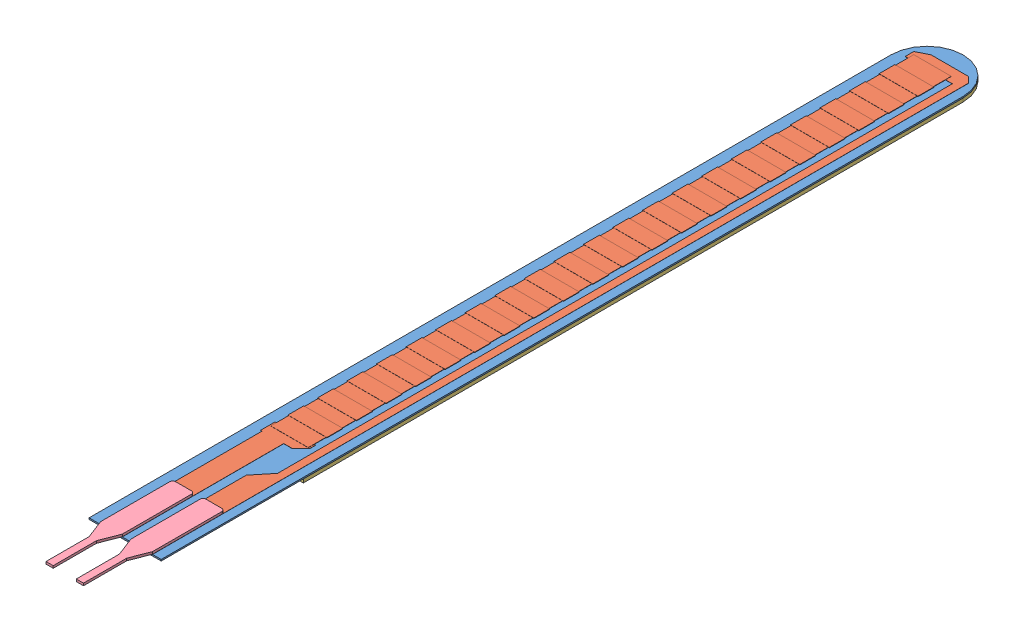
SolidWorks assembly FlexSensor, configuration Default. Lengths in mm.
Overall size (6.35 0.65 79.26).
5 component instances, 4 part files, 11 mates.
Components (placement in the parent):
- PlasticFilm-1: PlasticFilm [Default] at (-52.7883 12.8986 54.2802) size (6.35 0.13 73.81)
- Flex_Sensor_Circuit-1: Flex_Sensor_Circuit [Default] at origin size (4.83 0.04 72.39)
- Plastic_Stiffner-1: Plastic_Stiffner [Default] at (-52.7883 12.8986 54.2802) x (-1 0 0) z (0 -1 0) size (6.35 61.29 0.3)
- GoldProngTerminal-1: GoldProngTerminal [Default] at (0 13.0383 0) x (1 0 0) z (0 1 0) size (1.9 11.8 0.2)
- GoldProngTerminal-2: GoldProngTerminal [Default] at (-2.667 13.0383 0) x (1 0 0) z (0 1 0) size (1.9 11.8 0.2)
Mates (geometry in assembly coordinates):
- InPlace2: in place: plane of PlasticFilm-1 through (-49.6133 12.8986 -16.3572) normal (0 -1 0); plane of ? through (0 12.8986 0) normal (0 -1 0); moOrthogonalPlaneRef_w of PlasticFilm-1 through (-49.6133 12.8986 -16.3572) normal (0 -1 0); unknown of ?; plane of PlasticFilm-1 through (-49.6133 12.8986 -16.3572) normal (0 -1 0); line of ? through (-55 0 12.8986) axis (0 -1 0); plane of PlasticFilm-1 through (-49.6133 12.8986 -16.3572) normal (0 -1 0); unknown of Plastic_Stiffner-1
- Coincident4: coincident aligned: plane of PlasticFilm-1; plane of Plastic_Stiffner-1
- Coincident5: coincident aligned: moOrthogonalPlaneRef_w of PlasticFilm-1 through (-52.7883 12.8986 54.2802) normal (0 0 -1); plane of Plastic_Stiffner-1
- Coincident6: coincident anti-aligned: moOrthogonalPlaneRef_w of PlasticFilm-1 through (-52.7883 12.8986 54.2802) normal (1 0 0); plane of Plastic_Stiffner-1
- InPlace3: in place: plane of Flex_Sensor_Circuit-1 through (0 13.0383 0) normal (0 1 0); plane of GoldProngTerminal-1 through (0 13.0383 0) normal (0 1 0); plane of Flex_Sensor_Circuit-1 through (0 13.0383 0) normal (0 1 0); plane of GoldProngTerminal-1 through (0 13.0383 0) normal (0 0 -1); plane of Flex_Sensor_Circuit-1 through (0 13.0383 0) normal (0 1 0); line of GoldProngTerminal-1 through (-55 0 13.0383) axis (0 1 0); plane of Flex_Sensor_Circuit-1 through (0 13.0383 0) normal (0 1 0); unknown of GoldProngTerminal-1
- Coincident7: coincident aligned: plane of Flex_Sensor_Circuit-1; plane of GoldProngTerminal-1
- Coincident8: coincident aligned: moOrthogonalPlaneRef_w of Flex_Sensor_Circuit-1 through (0 13.0383 0) normal (0 0 -1); plane of GoldProngTerminal-1 through (0 13.0383 0) normal (0 0 -1)
- Coincident9: coincident anti-aligned: moOrthogonalPlaneRef_w of Flex_Sensor_Circuit-1 through (0 13.0383 0) normal (-1 0 0); plane of GoldProngTerminal-1
- Coincident13: coincident aligned: line of GoldProngTerminal-1 through (-47.4543 13.2415 47.9302) axis (-1 0 0); line of GoldProngTerminal-2 through (-50.1213 13.2415 47.9302) axis (-1 0 0)
- Coincident16: coincident anti-aligned: plane of Flex_Sensor_Circuit-1 through (0 13.0383 0) normal (0 1 0); plane of GoldProngTerminal-2 through (-2.667 13.0383 0) normal (0 -1 0)
- Coincident18: coincident aligned: plane of Flex_Sensor_Circuit-1 through (-49.8673 13.0383 54.2802) normal (1 0 0); plane of GoldProngTerminal-2 through (-49.8673 13.2415 54.2802) normal (1 0 0)
